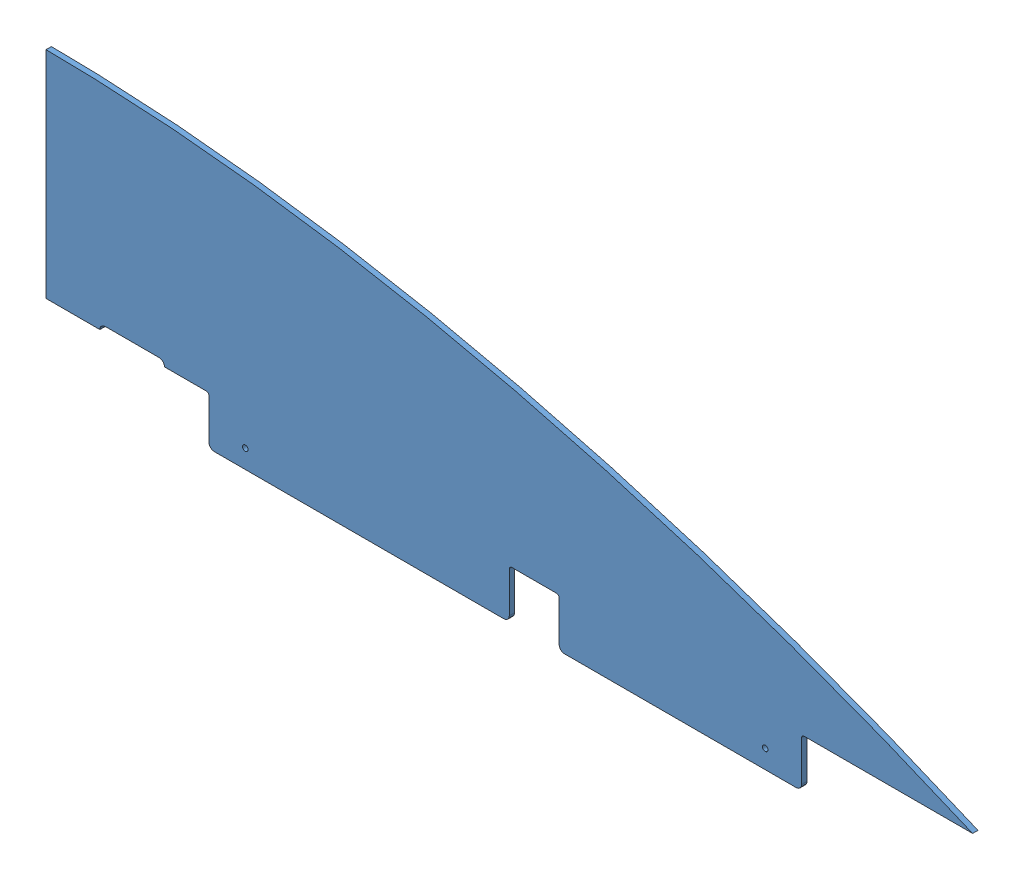
SolidWorks assembly GE-19082-Red, configuration Default. Lengths in mm.
Overall size (1092.2 311.15 57.4).
3 component instances, 3 part files, 6 mates.
Components (placement in the parent):
- GE-19082-1: GE-19082 [Default] at origin size (1092.2 311.15 6.35)
- GE-19082-Left-Red-Vinyl-1: GE-19082-Left-Red-Vinyl [Default] at (0 0 -0.127) size (1092.2 254 0.13)
- GE-19082-Right-Red-Vinyl-1: GE-19082-Right-Red-Vinyl [Default] at (0 0 6.35) size (1092.2 254 0.13)
Mates (geometry in assembly coordinates):
- Coincident1: coincident: plane of assembly; plane of assembly; plane of GE-19082-1 through (566.5746 179.041 6.35) normal (0 0 1); plane of GE-19082-Right-Red-Vinyl-1 through (566.5746 179.041 6.35) normal (0 0 -1)
- Coincident2: coincident: plane of assembly; plane of assembly; plane of GE-19082-1 through (566.5746 179.041 0) normal (0 0 -1); plane of GE-19082-Left-Red-Vinyl-1 through (566.5746 179.041 0) normal (0 0 1)
- Coincident3: coincident: plane of assembly; plane of assembly; plane of GE-19082-1 through (0 254 6.35) normal (-1 0 0); plane of GE-19082-Right-Red-Vinyl-1 through (0 254 6.477) normal (-1 0 0)
- Coincident4: coincident: plane of assembly; plane of assembly; plane of GE-19082-1 through (0 254 6.35) normal (-1 0 0); plane of GE-19082-Left-Red-Vinyl-1 through (0 254 0) normal (-1 0 0)
- Coincident5: coincident: plane of assembly; plane of assembly; plane of GE-19082-1 through (0 0 6.35) normal (0 -1 0); plane of GE-19082-Right-Red-Vinyl-1 through (0 0 6.477) normal (0 -1 0)
- Coincident6: coincident: plane of assembly; plane of assembly; plane of GE-19082-1 through (0 0 6.35) normal (0 -1 0); plane of GE-19082-Left-Red-Vinyl-1 through (0 0 0) normal (0 -1 0)
